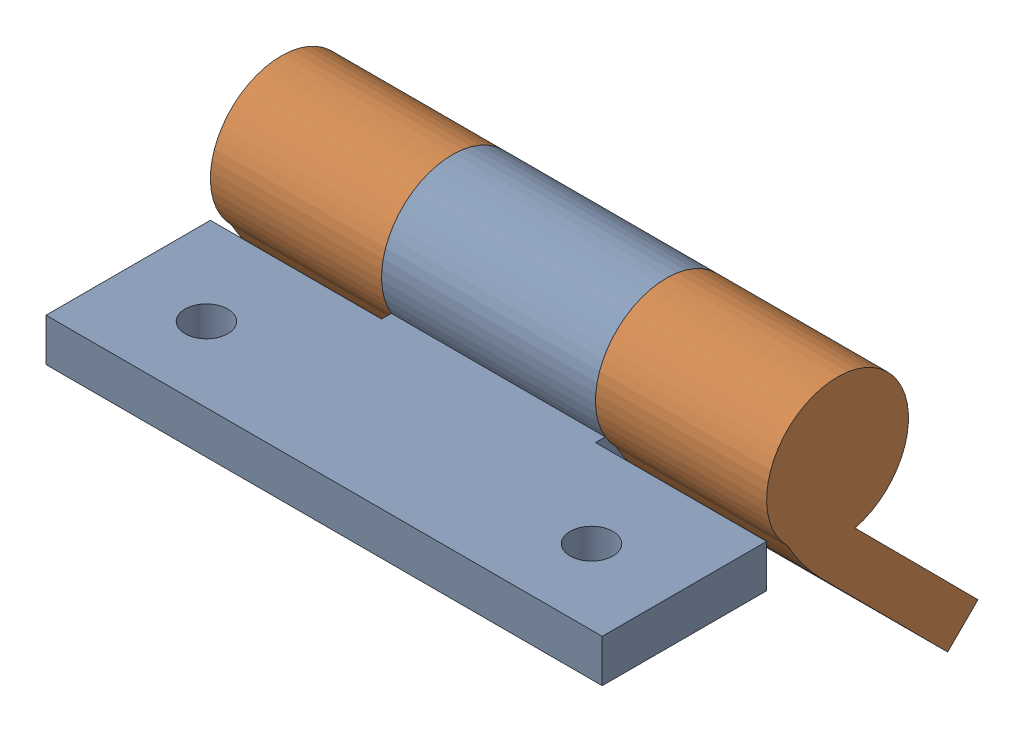
SolidWorks assembly DY-HY-阻尼合页, configuration 默认. Lengths in mm.
Overall size (26 15.08 21.11).
2 component instances, 2 part files, 2 mates.
Components (placement in the parent):
- DY-HE-合页1-1: DY-HE-合页1 [默认] at origin size (26 7 14.31)
- DY-HE-合页2-1: DY-HE-合页2 [默认] at (0 1.0855 2.6119) x (-1 0 0) z (0 -0.708783 -0.705426) size (26 7 14.31)
Mates (geometry in assembly coordinates):
- 同心1: concentric anti-aligned: cylinder of HE-合页1-1 through (-22.3762 3.685 0) axis (1 0 0) radius 3.315; cylinder of DY-HE-合页2-1 through (22.3762 3.685 0) axis (-1 0 0) radius 3.315
- 重合1: coincident anti-aligned: plane of HE-合页1-1 through (5 0 3.315) normal (1 0 0); plane of DY-HE-合页2-1 through (5 3.6974 5.2114) normal (-1 0 0)
